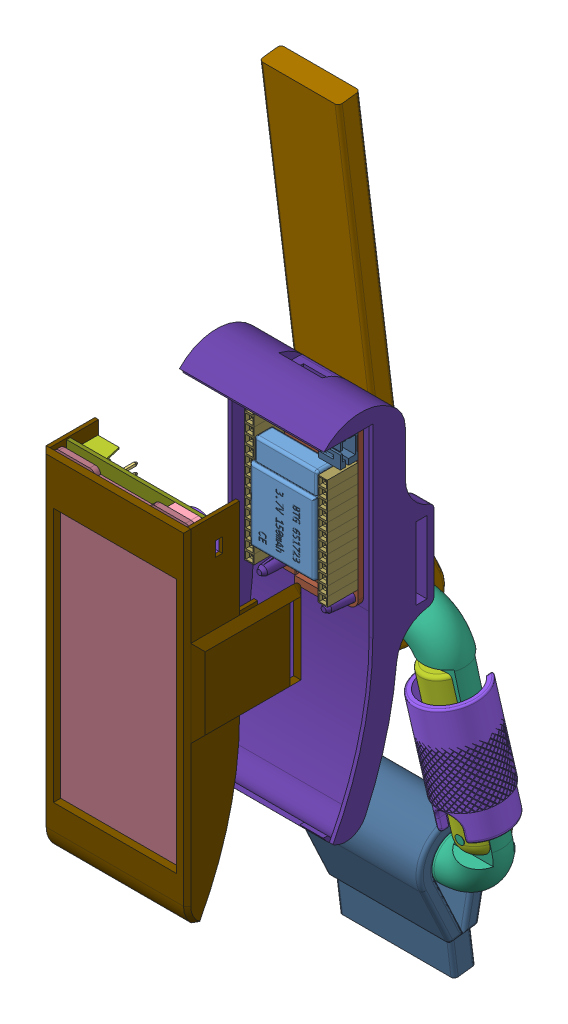
SolidWorks assembly PROTOTYPE4, configuration Default. Lengths in mm.
Overall size (66.23 222.78 90.92).
74 component instances, 29 part files, 212 mates.
Components (placement in the parent):
- P4_BTG 3.7V 150mAh LIPO-1: P4_BTG 3.7V 150mAh LIPO [Default] at (27.905 51.2971 -9.81) x (0 -1 0) z (-1 0 0) size (26 7 18.75)
- P4_CAPC-0805-T1.35-BN-1: P4_CAPC-0805-T1.35-BN [Default] at (18.3512 20.3637 36.1744) x (0 1 0) z (-1 0 0) size (2.1 1.35 1.35)
- P4_RESC-0805-1: P4_RESC-0805 [Default] at (24.182 63.4727 36.8494) x (-1 0 0) z (0 0 -1) size (2.1 1.35 0.6)
- P4_RESC-0805-2: P4_RESC-0805 [Default] at (24.1365 57.0909 36.8494) x (-1 0 0) z (0 0 -1) size (2.1 1.35 0.6)
- P4_RESC-0805-4: P4_RESC-0805 [Default] at (24.0502 60.9416 36.8494) x (1 0 0) z (0 0 -1) size (2.1 1.35 0.6)
- P4_soic-14-1: P4_soic-14 [Default] at (16.3896 59.7284 35.8715) x (0 -1 0) z (1 0 0) size (8.65 1.6 6.05)
- P4_MICRO_SD_WITH_SLOT-1: P4_MICRO_SD_WITH_SLOT [Default] at (56.0581 -187.6439 -84.5543) x (0 0 -1) z (0 1 0) size (2.44 17.9 16)
- P4_MS5611NOBREAKOUT-1: P4_MS5611NOBREAKOUT [Default] at (31.3803 12.3031 35.3494) x (0 1 0) z (-1 0 0) size (5.08 1.5 3.07)
- P4_TACTILE_SWITCH_SIDE-2: P4_TACTILE_SWITCH_SIDE [Default] at (3.8 59.5977 32.5638) x (0 1 0) z (0 0 1) size (6.8 8.34 8.73)
- P4_BOT-03D PASSIVE BUZZER-1: P4_BOT-03D PASSIVE BUZZER [Default] at (31.8 58.2086 36.5494) x (0 1 0) z (-1 0 0) size (12.6 3.6 11)
- P4_AB2_USB_MICRO_SMD-2: P4_AB2_USB_MICRO_SMD [Default] at (19.0065 148.0155 -12.6975) x (-1 0 0) z (0 1 0) size (7.99 3.56 5.59)
- P4_JST 2pin rightangle-2: P4_JST 2pin rightangle [Default] at (30.445 58.185 -12.31) x (0 1 0) z (1 0 0) size (8 6.3 7.62)
- P4_BLUEFRUIT FEATHER-2: P4_BLUEFRUIT FEATHER [Default] at (30.445 66 -13.81) x (0 -1 0) z (-1 0 0) size (50.98 4.5 22.86)
- P4_1PIN_8.25_SHORT_SOCKET-44: P4_1PIN_8.25_SHORT_SOCKET [Default] at (8.855 24 -12.31) x (0 1 0) z (0 0 1) size (2.54 2.54 11.81)
- P4_1PIN_8.25_SHORT_SOCKET-45: P4_1PIN_8.25_SHORT_SOCKET [Default] at (8.855 26.54 -12.31) x (0 1 0) z (0 0 1) size (2.54 2.54 11.81)
- P4_1PIN_8.25_SHORT_SOCKET-46: P4_1PIN_8.25_SHORT_SOCKET [Default] at (8.855 29.08 -12.31) x (0 1 0) z (0 0 1) size (2.54 2.54 11.81)
- P4_1PIN_8.25_SHORT_SOCKET-47: P4_1PIN_8.25_SHORT_SOCKET [Default] at (8.855 31.62 -12.31) x (0 1 0) z (0 0 1) size (2.54 2.54 11.81)
- P4_1PIN_8.25_SHORT_SOCKET-48: P4_1PIN_8.25_SHORT_SOCKET [Default] at (8.855 34.16 -12.31) x (0 1 0) z (0 0 1) size (2.54 2.54 11.81)
- P4_1PIN_8.25_SHORT_SOCKET-49: P4_1PIN_8.25_SHORT_SOCKET [Default] at (8.855 36.7 -12.31) x (0 1 0) z (0 0 1) size (2.54 2.54 11.81)
- P4_1PIN_8.25_SHORT_SOCKET-50: P4_1PIN_8.25_SHORT_SOCKET [Default] at (8.855 39.24 -12.31) x (0 1 0) z (0 0 1) size (2.54 2.54 11.81)
- P4_1PIN_8.25_SHORT_SOCKET-51: P4_1PIN_8.25_SHORT_SOCKET [Default] at (8.855 41.78 -12.31) x (0 1 0) z (0 0 1) size (2.54 2.54 11.81)
- P4_1PIN_8.25_SHORT_SOCKET-52: P4_1PIN_8.25_SHORT_SOCKET [Default] at (8.855 44.32 -12.31) x (0 1 0) z (0 0 1) size (2.54 2.54 11.81)
- P4_1PIN_8.25_SHORT_SOCKET-53: P4_1PIN_8.25_SHORT_SOCKET [Default] at (8.855 46.86 -12.31) x (0 1 0) z (0 0 1) size (2.54 2.54 11.81)
- P4_1PIN_8.25_SHORT_SOCKET-54: P4_1PIN_8.25_SHORT_SOCKET [Default] at (8.855 49.4 -12.31) x (0 1 0) z (0 0 1) size (2.54 2.54 11.81)
- P4_1PIN_8.25_SHORT_SOCKET-55: P4_1PIN_8.25_SHORT_SOCKET [Default] at (8.855 51.94 -12.31) x (0 1 0) z (0 0 1) size (2.54 2.54 11.81)
- P4_1PIN_8.25_SHORT_SOCKET-56: P4_1PIN_8.25_SHORT_SOCKET [Default] at (8.855 54.48 -12.31) x (0 1 0) z (0 0 1) size (2.54 2.54 11.81)
- P4_1PIN_8.25_SHORT_SOCKET-57: P4_1PIN_8.25_SHORT_SOCKET [Default] at (8.855 57.02 -12.31) x (0 1 0) z (0 0 1) size (2.54 2.54 11.81)
- P4_1PIN_8.25_SHORT_SOCKET-58: P4_1PIN_8.25_SHORT_SOCKET [Default] at (8.855 59.56 -12.31) x (0 1 0) z (0 0 1) size (2.54 2.54 11.81)
- P4_1PIN_8.25_SHORT_SOCKET-59: P4_1PIN_8.25_SHORT_SOCKET [Default] at (8.855 21.46 -12.31) x (0 1 0) z (0 0 1) size (2.54 2.54 11.81)
- P4_1PIN_8.25_SHORT_SOCKET-60: P4_1PIN_8.25_SHORT_SOCKET [Default] at (29.175 49.4 -12.31) x (0 1 0) z (0 0 1) size (2.54 2.54 11.81)
- P4_1PIN_8.25_SHORT_SOCKET-61: P4_1PIN_8.25_SHORT_SOCKET [Default] at (29.175 46.86 -12.31) x (0 1 0) z (0 0 1) size (2.54 2.54 11.81)
- P4_1PIN_8.25_SHORT_SOCKET-62: P4_1PIN_8.25_SHORT_SOCKET [Default] at (29.175 44.32 -12.31) x (0 1 0) z (0 0 1) size (2.54 2.54 11.81)
- P4_1PIN_8.25_SHORT_SOCKET-63: P4_1PIN_8.25_SHORT_SOCKET [Default] at (29.175 41.78 -12.31) x (0 1 0) z (0 0 1) size (2.54 2.54 11.81)
- P4_1PIN_8.25_SHORT_SOCKET-64: P4_1PIN_8.25_SHORT_SOCKET [Default] at (29.175 39.24 -12.31) x (0 1 0) z (0 0 1) size (2.54 2.54 11.81)
- P4_1PIN_8.25_SHORT_SOCKET-65: P4_1PIN_8.25_SHORT_SOCKET [Default] at (29.175 36.7 -12.31) x (0 1 0) z (0 0 1) size (2.54 2.54 11.81)
- P4_1PIN_8.25_SHORT_SOCKET-66: P4_1PIN_8.25_SHORT_SOCKET [Default] at (29.175 34.16 -12.31) x (0 1 0) z (0 0 1) size (2.54 2.54 11.81)
- P4_1PIN_8.25_SHORT_SOCKET-67: P4_1PIN_8.25_SHORT_SOCKET [Default] at (29.175 31.62 -12.31) x (0 1 0) z (0 0 1) size (2.54 2.54 11.81)
- P4_1PIN_8.25_SHORT_SOCKET-68: P4_1PIN_8.25_SHORT_SOCKET [Default] at (29.175 29.08 -12.31) x (0 1 0) z (0 0 1) size (2.54 2.54 11.81)
- P4_1PIN_8.25_SHORT_SOCKET-69: P4_1PIN_8.25_SHORT_SOCKET [Default] at (29.175 26.54 -12.31) x (0 1 0) z (0 0 1) size (2.54 2.54 11.81)
- P4_1PIN_8.25_SHORT_SOCKET-70: P4_1PIN_8.25_SHORT_SOCKET [Default] at (29.175 24 -12.31) x (0 1 0) z (0 0 1) size (2.54 2.54 11.81)
- P4_1PIN_8.25_SHORT_SOCKET-71: P4_1PIN_8.25_SHORT_SOCKET [Default] at (29.175 21.46 -12.31) x (0 1 0) z (0 0 1) size (2.54 2.54 11.81)
- Part2^PROTOTYPE4-1: Part2^PROTOTYPE4 [Default] at origin (virtual)
- P4_2.9_EPD-1: P4_2.9_EPD [Default] at (38 66.02 39.9794) x (-1 0 0) z (0 1 0) size (38 8.3 89.5)
  - P4_2.9_EPD-1: P4_2.9_EPD [Default] at origin size (38 3.55 89.5)
  - P4_JST XH 8 S8B-XH-A1 shrouded header connector v4-1: P4_JST XH 8 S8B-XH-A1 shrouded header connector v4 [Default] at (19 -2.875 -82.5) x (-1 0 0) z (0 0 -1) size (22.68 5.75 10.45)
  - P4_FPC_24-1: P4_FPC_24 [Valor predeterminado] at (23 -2.13 -7.2471) x (1 0 0) z (0 1 0) size (16.4 6.45 2.13)
- P4_PCB_FOR_2.9_EPD-1: P4_PCB_FOR_2.9_EPD [Default] at (0 66 37.8494) x (1 0 0) z (0 1 0) size (38 1 66)
- P4_2.9_EPD_CASE_BACK-1: P4_2.9_EPD_CASE_BACK [Default] at (38.015 -27.6516 -35.2894) x (0 1 0) z (-1 0 0) size (100.85 30.49 40)
- P4_2.9_EPD_CASE_COVER-1: P4_2.9_EPD_CASE_COVER [Default] at (0 -6.6251 42.5294) x (0 1 0) z (0 0 1) size (95.4 44 31.49)
- P4_SO8-1: P4_SO8 [Default] at (15.2666 50.6882 36.8494) x (1 0 0) z (0 1 0) size (5 1.75 6.2)
- P4_SOT23-1: P4_SOT23 [Predeterminado] at (22.8563 53.2581 36.1768) x (-1 0 0) z (0 0 -1) size (3 2.25 1.22)
- P4_RESC-0805-8: P4_RESC-0805 [Default] at (22.7629 48.0366 36.8494) x (0 1 0) z (0 0 -1) size (2.1 1.35 0.6)
- P4_878980426-1: P4_878980426 [Default] at (8.84 35.43 34.2844) x (0 1 0) z (-1 0 0) size (10.16 9.65 4.8)
- P4_878980426-2: P4_878980426 [Default] at (8.84 25.27 34.2844) x (0 1 0) z (-1 0 0) size (10.16 9.65 4.8)
- P4_878980426-3: P4_878980426 [Default] at (29.16 35.43 34.2844) x (0 1 0) z (-1 0 0) size (10.16 9.65 4.8)
- P4_878980426-4: P4_878980426 [Default] at (8.84 55.75 34.2844) x (0 1 0) z (-1 0 0) size (10.16 9.65 4.8)
- P4_878980426-5: P4_878980426 [Default] at (29.16 45.59 34.2844) x (0 1 0) z (-1 0 0) size (10.16 9.65 4.8)
- P4_878980426-6: P4_878980426 [Default] at (29.16 25.27 34.2844) x (0 1 0) z (-1 0 0) size (10.16 9.65 4.8)
- P4_878980426-7: P4_878980426 [Default] at (8.84 45.59 34.2844) x (0 1 0) z (-1 0 0) size (10.16 9.65 4.8)
- P4_SPACER-1: P4_SPACER [Default] at (38 -23.48 39.9794) x (-1 0 0) z (0 -1 0) size (38 3.13 70.25)
- P4_SMT_RA_PIN-1: P4_SMT_RA_PIN [Default] at (24.03 10.67 36.8494) x (0 -1 0) z (1 0 0) size (12.95 3.56 2.54)
- P4_SMT_RA_PIN-2: P4_SMT_RA_PIN [Default] at (26.57 10.67 36.8494) x (0 -1 0) z (1 0 0) size (12.95 3.56 2.54)
- P4_SMT_RA_PIN-3: P4_SMT_RA_PIN [Default] at (18.95 10.67 36.8494) x (0 -1 0) z (1 0 0) size (12.95 3.56 2.54)
- P4_SMT_RA_PIN-4: P4_SMT_RA_PIN [Default] at (21.49 10.67 36.8494) x (0 -1 0) z (1 0 0) size (12.95 3.56 2.54)
- P4_SMT_RA_PIN-5: P4_SMT_RA_PIN [Default] at (31.65 10.67 36.8494) x (0 -1 0) z (1 0 0) size (12.95 3.56 2.54)
- P4_SMT_RA_PIN-6: P4_SMT_RA_PIN [Default] at (29.11 10.67 36.8494) x (0 -1 0) z (1 0 0) size (12.95 3.56 2.54)
- P4_SMT_RA_PIN-7: P4_SMT_RA_PIN [Default] at (36.73 10.67 36.8494) x (0 -1 0) z (1 0 0) size (12.95 3.56 2.54)
- P4_SMT_RA_PIN-8: P4_SMT_RA_PIN [Default] at (34.19 10.67 36.8494) x (0 -1 0) z (1 0 0) size (12.95 3.56 2.54)
- CARABINER SUP AIR-1: CARABINER SUP AIR [Default] at (19.0561 -21.0823 -30.0124) x (1 0 0) z (0 -0.122208 0.992504) size (66.23 74 18.01)
  - CARABINER_MAIN-1: CARABINER_MAIN [Default] at origin size (63.85 74 12.79)
  - CARABINER_ARM-1: CARABINER_ARM [Default] at (26.2233 -22.952 0) x (0.990404 0.138202 0) z (0 0 1) size (12 45.37 12.12)
  - CARABINER_LOCK-1: CARABINER_LOCK [Default] at (25.3718 -16.8504 0) x (0.990404 0.138202 0) z (0 0 1) size (18.01 33.07 18.01)
- RISER-1: RISER [Default] at (7.015 9.6853 -26.2239) x (1 0 0) z (0 -0.122208 0.992504) size (24 140 20)
- HARNESS-1: HARNESS [Default] at (1.9827 -51.85 -33.8009) x (1 0 0) z (0 0.122208 -0.992504) size (34 40 20)
Mates (geometry in assembly coordinates):
- Coincident628: coincident anti-aligned: plane of P4_BTG 3.7V 150mAh LIPO-1 through (27.905 51.2971 -9.81) normal (0 0 -1); plane of P4_BLUEFRUIT FEATHER-2 through (30.445 66 -9.81) normal (0 0 1)
- Coincident376: coincident aligned: plane of P4_PCB_FOR_2.9_EPD-1 through (0 66 36.8494) normal (-1 0 0); plane of P4_TACTILE_SWITCH_SIDE-2 through (0 59.5977 32.5638) normal (-1 0 0)
- Coincident433: coincident anti-aligned: plane of P4_AB2_USB_MICRO_SMD-2 through (19.0065 66 -12.31) normal (0 0 -1); plane of P4_BLUEFRUIT FEATHER-2 through (27.815 17.65 -12.31) normal (0 0 1)
- Parallel22: parallel aligned: line of P4_AB2_USB_MICRO_SMD-2 through (21.4522 66 -12.3752) axis (-1 0 0); line of P4_BLUEFRUIT FEATHER-2 through (27.815 66 -12.31) axis (-1 0 0)
- Coincident434: coincident aligned: plane of P4_JST 2pin rightangle-2 through (30.445 52.4192 -12.31) normal (1 0 0); plane of P4_BLUEFRUIT FEATHER-2 through (30.445 63.37 -12.31) normal (1 0 0)
- Coincident435: coincident: line of P4_AB2_USB_MICRO_SMD-2 through (21.9513 66 -9.7692) axis (-1 0 0); plane of P4_BLUEFRUIT FEATHER-2 through (27.815 66 -12.31) normal (0 1 0)
- Coincident436: coincident anti-aligned: plane of P4_JST 2pin rightangle-2 through (26.635 55.3021 -12.31) normal (0 0 -1); plane of P4_BLUEFRUIT FEATHER-2 through (27.815 17.65 -12.31) normal (0 0 1)
- Distance27: distance = 6.7 mm aligned: plane of P4_JST 2pin rightangle-2 through (30.445 59.3 -12.31) normal (0 1 0); plane of P4_BLUEFRUIT FEATHER-2 through (27.815 66 -12.31) normal (0 1 0)
- Parallel23: parallel aligned: plane of P4_BOT-03D PASSIVE BUZZER-1 through (38 55.7086 33.2494) normal (1 0 0); plane of P4_BLUEFRUIT FEATHER-2 through (30.445 63.37 -12.31) normal (1 0 0)
- LimitDistance11: limit distance = 0.0071 mm anti-aligned: plane of P4_BTG 3.7V 150mAh LIPO-1 through (27.905 51.2971 -2.81) normal (0 1 0); plane of P4_JST 2pin rightangle-2 through (30.445 51.3042 -12.31) normal (0 -1 0)
- Coincident458: coincident aligned: plane of P4_1PIN_8.25_SHORT_SOCKET-57 through (7.585 57.02 -3.81) normal (-1 0 0); plane of P4_1PIN_8.25_SHORT_SOCKET-58 through (7.585 59.56 -3.81) normal (-1 0 0)
- Coincident459: coincident aligned: plane of P4_1PIN_8.25_SHORT_SOCKET-56 through (7.585 54.48 -3.81) normal (-1 0 0); plane of P4_1PIN_8.25_SHORT_SOCKET-57 through (7.585 57.02 -3.81) normal (-1 0 0)
- Coincident460: coincident aligned: plane of P4_1PIN_8.25_SHORT_SOCKET-55 through (7.585 51.94 -3.81) normal (-1 0 0); plane of P4_1PIN_8.25_SHORT_SOCKET-56 through (7.585 54.48 -3.81) normal (-1 0 0)
- Coincident461: coincident aligned: plane of P4_1PIN_8.25_SHORT_SOCKET-54 through (7.585 49.4 -3.81) normal (-1 0 0); plane of P4_1PIN_8.25_SHORT_SOCKET-55 through (7.585 51.94 -3.81) normal (-1 0 0)
- Coincident462: coincident aligned: plane of P4_1PIN_8.25_SHORT_SOCKET-53 through (7.585 46.86 -3.81) normal (-1 0 0); plane of P4_1PIN_8.25_SHORT_SOCKET-54 through (7.585 49.4 -3.81) normal (-1 0 0)
- Coincident463: coincident aligned: plane of P4_1PIN_8.25_SHORT_SOCKET-52 through (7.585 44.32 -3.81) normal (-1 0 0); plane of P4_1PIN_8.25_SHORT_SOCKET-53 through (7.585 46.86 -3.81) normal (-1 0 0)
- Coincident464: coincident aligned: plane of P4_1PIN_8.25_SHORT_SOCKET-51 through (7.585 41.78 -3.81) normal (-1 0 0); plane of P4_1PIN_8.25_SHORT_SOCKET-52 through (7.585 44.32 -3.81) normal (-1 0 0)
- Coincident465: coincident aligned: plane of P4_1PIN_8.25_SHORT_SOCKET-50 through (7.585 39.24 -3.81) normal (-1 0 0); plane of P4_1PIN_8.25_SHORT_SOCKET-51 through (7.585 41.78 -3.81) normal (-1 0 0)
- Coincident466: coincident aligned: plane of P4_1PIN_8.25_SHORT_SOCKET-49 through (7.585 36.7 -3.81) normal (-1 0 0); plane of P4_1PIN_8.25_SHORT_SOCKET-50 through (7.585 39.24 -3.81) normal (-1 0 0)
- Coincident467: coincident aligned: plane of P4_1PIN_8.25_SHORT_SOCKET-48 through (7.585 34.16 -3.81) normal (-1 0 0); plane of P4_1PIN_8.25_SHORT_SOCKET-49 through (7.585 36.7 -3.81) normal (-1 0 0)
- Coincident468: coincident aligned: plane of P4_1PIN_8.25_SHORT_SOCKET-47 through (7.585 31.62 -3.81) normal (-1 0 0); plane of P4_1PIN_8.25_SHORT_SOCKET-48 through (7.585 34.16 -3.81) normal (-1 0 0)
- Coincident469: coincident aligned: plane of P4_1PIN_8.25_SHORT_SOCKET-46 through (7.585 29.08 -3.81) normal (-1 0 0); plane of P4_1PIN_8.25_SHORT_SOCKET-47 through (7.585 31.62 -3.81) normal (-1 0 0)
- Coincident470: coincident aligned: plane of P4_1PIN_8.25_SHORT_SOCKET-45 through (7.585 26.54 -3.81) normal (-1 0 0); plane of P4_1PIN_8.25_SHORT_SOCKET-46 through (7.585 29.08 -3.81) normal (-1 0 0)
- Coincident471: coincident aligned: plane of P4_1PIN_8.25_SHORT_SOCKET-44 through (7.585 24 -3.81) normal (-1 0 0); plane of P4_1PIN_8.25_SHORT_SOCKET-45 through (7.585 26.54 -3.81) normal (-1 0 0)
- Coincident472: coincident anti-aligned: plane of P4_1PIN_8.25_SHORT_SOCKET-57 through (8.855 58.29 -3.81) normal (0 1 0); plane of P4_1PIN_8.25_SHORT_SOCKET-58 through (8.855 58.29 -3.81) normal (0 -1 0)
- Coincident473: coincident anti-aligned: plane of P4_1PIN_8.25_SHORT_SOCKET-56 through (8.855 55.75 -3.81) normal (0 1 0); plane of P4_1PIN_8.25_SHORT_SOCKET-57 through (8.855 55.75 -3.81) normal (0 -1 0)
- Coincident474: coincident anti-aligned: plane of P4_1PIN_8.25_SHORT_SOCKET-55 through (8.855 53.21 -3.81) normal (0 1 0); plane of P4_1PIN_8.25_SHORT_SOCKET-56 through (8.855 53.21 -3.81) normal (0 -1 0)
- Coincident475: coincident anti-aligned: plane of P4_1PIN_8.25_SHORT_SOCKET-54 through (8.855 50.67 -3.81) normal (0 1 0); plane of P4_1PIN_8.25_SHORT_SOCKET-55 through (8.855 50.67 -3.81) normal (0 -1 0)
- Coincident476: coincident anti-aligned: plane of P4_1PIN_8.25_SHORT_SOCKET-53 through (8.855 48.13 -3.81) normal (0 1 0); plane of P4_1PIN_8.25_SHORT_SOCKET-54 through (8.855 48.13 -3.81) normal (0 -1 0)
- Coincident477: coincident anti-aligned: plane of P4_1PIN_8.25_SHORT_SOCKET-52 through (8.855 45.59 -3.81) normal (0 1 0); plane of P4_1PIN_8.25_SHORT_SOCKET-53 through (8.855 45.59 -3.81) normal (0 -1 0)
- Coincident478: coincident anti-aligned: plane of P4_1PIN_8.25_SHORT_SOCKET-51 through (8.855 43.05 -3.81) normal (0 1 0); plane of P4_1PIN_8.25_SHORT_SOCKET-52 through (8.855 43.05 -3.81) normal (0 -1 0)
- Coincident479: coincident anti-aligned: plane of P4_1PIN_8.25_SHORT_SOCKET-50 through (8.855 40.51 -3.81) normal (0 1 0); plane of P4_1PIN_8.25_SHORT_SOCKET-51 through (8.855 40.51 -3.81) normal (0 -1 0)
- Coincident480: coincident anti-aligned: plane of P4_1PIN_8.25_SHORT_SOCKET-49 through (8.855 37.97 -3.81) normal (0 1 0); plane of P4_1PIN_8.25_SHORT_SOCKET-50 through (8.855 37.97 -3.81) normal (0 -1 0)
- Coincident481: coincident anti-aligned: plane of P4_1PIN_8.25_SHORT_SOCKET-48 through (8.855 35.43 -3.81) normal (0 1 0); plane of P4_1PIN_8.25_SHORT_SOCKET-49 through (8.855 35.43 -3.81) normal (0 -1 0)
- Coincident482: coincident anti-aligned: plane of P4_1PIN_8.25_SHORT_SOCKET-47 through (8.855 32.89 -3.81) normal (0 1 0); plane of P4_1PIN_8.25_SHORT_SOCKET-48 through (8.855 32.89 -3.81) normal (0 -1 0)
- Coincident483: coincident anti-aligned: plane of P4_1PIN_8.25_SHORT_SOCKET-46 through (8.855 30.35 -3.81) normal (0 1 0); plane of P4_1PIN_8.25_SHORT_SOCKET-47 through (8.855 30.35 -3.81) normal (0 -1 0)
- Coincident484: coincident anti-aligned: plane of P4_1PIN_8.25_SHORT_SOCKET-45 through (8.855 27.81 -3.81) normal (0 1 0); plane of P4_1PIN_8.25_SHORT_SOCKET-46 through (8.855 27.81 -3.81) normal (0 -1 0)
- Coincident485: coincident anti-aligned: plane of P4_1PIN_8.25_SHORT_SOCKET-44 through (8.855 25.27 -3.81) normal (0 1 0); plane of P4_1PIN_8.25_SHORT_SOCKET-45 through (8.855 25.27 -3.81) normal (0 -1 0)
- Coincident486: coincident aligned: plane of P4_1PIN_8.25_SHORT_SOCKET-57 through (8.855 57.02 -3.81) normal (0 0 1); plane of P4_1PIN_8.25_SHORT_SOCKET-58 through (8.855 59.56 -3.81) normal (0 0 1)
- Coincident487: coincident aligned: plane of P4_1PIN_8.25_SHORT_SOCKET-56 through (8.855 54.48 -3.81) normal (0 0 1); plane of P4_1PIN_8.25_SHORT_SOCKET-57 through (8.855 57.02 -3.81) normal (0 0 1)
- Coincident488: coincident aligned: plane of P4_1PIN_8.25_SHORT_SOCKET-55 through (8.855 51.94 -3.81) normal (0 0 1); plane of P4_1PIN_8.25_SHORT_SOCKET-56 through (8.855 54.48 -3.81) normal (0 0 1)
- Coincident489: coincident aligned: plane of P4_1PIN_8.25_SHORT_SOCKET-54 through (8.855 49.4 -3.81) normal (0 0 1); plane of P4_1PIN_8.25_SHORT_SOCKET-55 through (8.855 51.94 -3.81) normal (0 0 1)
- Coincident490: coincident aligned: plane of P4_1PIN_8.25_SHORT_SOCKET-53 through (8.855 46.86 -3.81) normal (0 0 1); plane of P4_1PIN_8.25_SHORT_SOCKET-54 through (8.855 49.4 -3.81) normal (0 0 1)
- Coincident491: coincident aligned: plane of P4_1PIN_8.25_SHORT_SOCKET-52 through (8.855 44.32 -3.81) normal (0 0 1); plane of P4_1PIN_8.25_SHORT_SOCKET-53 through (8.855 46.86 -3.81) normal (0 0 1)
- Coincident492: coincident aligned: plane of P4_1PIN_8.25_SHORT_SOCKET-51 through (8.855 41.78 -3.81) normal (0 0 1); plane of P4_1PIN_8.25_SHORT_SOCKET-52 through (8.855 44.32 -3.81) normal (0 0 1)
- Coincident493: coincident aligned: plane of P4_1PIN_8.25_SHORT_SOCKET-50 through (8.855 39.24 -3.81) normal (0 0 1); plane of P4_1PIN_8.25_SHORT_SOCKET-51 through (8.855 41.78 -3.81) normal (0 0 1)
- Coincident494: coincident aligned: plane of P4_1PIN_8.25_SHORT_SOCKET-49 through (8.855 36.7 -3.81) normal (0 0 1); plane of P4_1PIN_8.25_SHORT_SOCKET-50 through (8.855 39.24 -3.81) normal (0 0 1)
- Coincident495: coincident aligned: plane of P4_1PIN_8.25_SHORT_SOCKET-48 through (8.855 34.16 -3.81) normal (0 0 1); plane of P4_1PIN_8.25_SHORT_SOCKET-49 through (8.855 36.7 -3.81) normal (0 0 1)
- Coincident496: coincident aligned: plane of P4_1PIN_8.25_SHORT_SOCKET-47 through (8.855 31.62 -3.81) normal (0 0 1); plane of P4_1PIN_8.25_SHORT_SOCKET-48 through (8.855 34.16 -3.81) normal (0 0 1)
- Coincident497: coincident aligned: plane of P4_1PIN_8.25_SHORT_SOCKET-46 through (8.855 29.08 -3.81) normal (0 0 1); plane of P4_1PIN_8.25_SHORT_SOCKET-47 through (8.855 31.62 -3.81) normal (0 0 1)
- Coincident498: coincident aligned: plane of P4_1PIN_8.25_SHORT_SOCKET-45 through (8.855 26.54 -3.81) normal (0 0 1); plane of P4_1PIN_8.25_SHORT_SOCKET-46 through (8.855 29.08 -3.81) normal (0 0 1)
- Coincident499: coincident aligned: plane of P4_1PIN_8.25_SHORT_SOCKET-44 through (8.855 24 -3.81) normal (0 0 1); plane of P4_1PIN_8.25_SHORT_SOCKET-45 through (8.855 26.54 -3.81) normal (0 0 1)
- Coincident500: coincident anti-aligned: plane of P4_BLUEFRUIT FEATHER-2 through (27.815 17.65 -12.31) normal (0 0 1); plane of P4_1PIN_8.25_SHORT_SOCKET-44 through (8.855 24 -12.31) normal (0 0 -1)
- Coincident501: coincident aligned: plane of P4_1PIN_8.25_SHORT_SOCKET-58 through (7.585 59.56 -3.81) normal (-1 0 0); plane of P4_BLUEFRUIT FEATHER-2 through (7.585 63.37 -12.31) normal (-1 0 0)
- Coincident502: coincident aligned: plane of P4_1PIN_8.25_SHORT_SOCKET-44 through (7.585 24 -3.81) normal (-1 0 0); plane of P4_1PIN_8.25_SHORT_SOCKET-59 through (7.585 21.46 -3.81) normal (-1 0 0)
- Coincident503: coincident anti-aligned: plane of P4_1PIN_8.25_SHORT_SOCKET-44 through (8.855 22.73 -3.81) normal (0 -1 0); plane of P4_1PIN_8.25_SHORT_SOCKET-59 through (8.855 22.73 -3.81) normal (0 1 0)
- Coincident504: coincident aligned: plane of P4_1PIN_8.25_SHORT_SOCKET-44 through (8.855 24 -3.81) normal (0 0 1); plane of P4_1PIN_8.25_SHORT_SOCKET-59 through (8.855 21.46 -3.81) normal (0 0 1)
- Width9: width anti-aligned: plane of P4_1PIN_8.25_SHORT_SOCKET-58 through (8.855 60.83 -3.81) normal (0 1 0); plane of P4_1PIN_8.25_SHORT_SOCKET-59 through (8.855 20.19 -3.81) normal (0 -1 0); plane of P4_BLUEFRUIT FEATHER-2 through (27.815 15.02 -12.31) normal (0 -1 0); plane of P4_BLUEFRUIT FEATHER-2 through (27.815 66 -12.31) normal (0 1 0)
- Coincident505: coincident anti-aligned: plane of P4_1PIN_8.25_SHORT_SOCKET-60 through (29.175 48.13 -3.81) normal (0 -1 0); plane of P4_1PIN_8.25_SHORT_SOCKET-61 through (29.175 48.13 -3.81) normal (0 1 0)
- Coincident506: coincident anti-aligned: plane of P4_1PIN_8.25_SHORT_SOCKET-70 through (29.175 22.73 -3.81) normal (0 -1 0); plane of P4_1PIN_8.25_SHORT_SOCKET-71 through (29.175 22.73 -3.81) normal (0 1 0)
- Coincident507: coincident aligned: plane of P4_1PIN_8.25_SHORT_SOCKET-63 through (27.905 41.78 -3.81) normal (-1 0 0); plane of P4_1PIN_8.25_SHORT_SOCKET-64 through (27.905 39.24 -3.81) normal (-1 0 0)
- Coincident508: coincident aligned: plane of P4_1PIN_8.25_SHORT_SOCKET-61 through (27.905 46.86 -3.81) normal (-1 0 0); plane of P4_1PIN_8.25_SHORT_SOCKET-62 through (27.905 44.32 -3.81) normal (-1 0 0)
- Coincident509: coincident aligned: plane of P4_1PIN_8.25_SHORT_SOCKET-62 through (27.905 44.32 -3.81) normal (-1 0 0); plane of P4_1PIN_8.25_SHORT_SOCKET-63 through (27.905 41.78 -3.81) normal (-1 0 0)
- Coincident510: coincident aligned: plane of P4_1PIN_8.25_SHORT_SOCKET-66 through (27.905 34.16 -3.81) normal (-1 0 0); plane of P4_1PIN_8.25_SHORT_SOCKET-67 through (27.905 31.62 -3.81) normal (-1 0 0)
- Coincident511: coincident aligned: plane of P4_1PIN_8.25_SHORT_SOCKET-65 through (27.905 36.7 -3.81) normal (-1 0 0); plane of P4_1PIN_8.25_SHORT_SOCKET-66 through (27.905 34.16 -3.81) normal (-1 0 0)
- Coincident512: coincident aligned: plane of P4_1PIN_8.25_SHORT_SOCKET-68 through (27.905 29.08 -3.81) normal (-1 0 0); plane of P4_1PIN_8.25_SHORT_SOCKET-69 through (27.905 26.54 -3.81) normal (-1 0 0)
- Coincident513: coincident aligned: plane of P4_1PIN_8.25_SHORT_SOCKET-67 through (27.905 31.62 -3.81) normal (-1 0 0); plane of P4_1PIN_8.25_SHORT_SOCKET-68 through (27.905 29.08 -3.81) normal (-1 0 0)
- Coincident514: coincident aligned: plane of P4_1PIN_8.25_SHORT_SOCKET-69 through (27.905 26.54 -3.81) normal (-1 0 0); plane of P4_1PIN_8.25_SHORT_SOCKET-70 through (27.905 24 -3.81) normal (-1 0 0)
- Coincident515: coincident aligned: plane of P4_1PIN_8.25_SHORT_SOCKET-70 through (27.905 24 -3.81) normal (-1 0 0); plane of P4_1PIN_8.25_SHORT_SOCKET-71 through (27.905 21.46 -3.81) normal (-1 0 0)
- Coincident516: coincident aligned: plane of P4_1PIN_8.25_SHORT_SOCKET-60 through (27.905 49.4 -3.81) normal (-1 0 0); plane of P4_1PIN_8.25_SHORT_SOCKET-61 through (27.905 46.86 -3.81) normal (-1 0 0)
- Coincident517: coincident aligned: plane of P4_1PIN_8.25_SHORT_SOCKET-64 through (27.905 39.24 -3.81) normal (-1 0 0); plane of P4_1PIN_8.25_SHORT_SOCKET-65 through (27.905 36.7 -3.81) normal (-1 0 0)
- Coincident518: coincident anti-aligned: plane of P4_1PIN_8.25_SHORT_SOCKET-62 through (29.175 43.05 -3.81) normal (0 -1 0); plane of P4_1PIN_8.25_SHORT_SOCKET-63 through (29.175 43.05 -3.81) normal (0 1 0)
- Coincident519: coincident anti-aligned: plane of P4_1PIN_8.25_SHORT_SOCKET-63 through (29.175 40.51 -3.81) normal (0 -1 0); plane of P4_1PIN_8.25_SHORT_SOCKET-64 through (29.175 40.51 -3.81) normal (0 1 0)
- Coincident520: coincident anti-aligned: plane of P4_1PIN_8.25_SHORT_SOCKET-65 through (29.175 35.43 -3.81) normal (0 -1 0); plane of P4_1PIN_8.25_SHORT_SOCKET-66 through (29.175 35.43 -3.81) normal (0 1 0)
- Coincident521: coincident anti-aligned: plane of P4_1PIN_8.25_SHORT_SOCKET-66 through (29.175 32.89 -3.81) normal (0 -1 0); plane of P4_1PIN_8.25_SHORT_SOCKET-67 through (29.175 32.89 -3.81) normal (0 1 0)
- Coincident522: coincident anti-aligned: plane of P4_1PIN_8.25_SHORT_SOCKET-61 through (29.175 45.59 -3.81) normal (0 -1 0); plane of P4_1PIN_8.25_SHORT_SOCKET-62 through (29.175 45.59 -3.81) normal (0 1 0)
- Coincident523: coincident anti-aligned: plane of P4_1PIN_8.25_SHORT_SOCKET-67 through (29.175 30.35 -3.81) normal (0 -1 0); plane of P4_1PIN_8.25_SHORT_SOCKET-68 through (29.175 30.35 -3.81) normal (0 1 0)
- Coincident524: coincident anti-aligned: plane of P4_1PIN_8.25_SHORT_SOCKET-69 through (29.175 25.27 -3.81) normal (0 -1 0); plane of P4_1PIN_8.25_SHORT_SOCKET-70 through (29.175 25.27 -3.81) normal (0 1 0)
- Coincident525: coincident anti-aligned: plane of P4_1PIN_8.25_SHORT_SOCKET-64 through (29.175 37.97 -3.81) normal (0 -1 0); plane of P4_1PIN_8.25_SHORT_SOCKET-65 through (29.175 37.97 -3.81) normal (0 1 0)
- Coincident526: coincident anti-aligned: plane of P4_1PIN_8.25_SHORT_SOCKET-68 through (29.175 27.81 -3.81) normal (0 -1 0); plane of P4_1PIN_8.25_SHORT_SOCKET-69 through (29.175 27.81 -3.81) normal (0 1 0)
- Coincident527: coincident aligned: plane of P4_1PIN_8.25_SHORT_SOCKET-65 through (29.175 36.7 -3.81) normal (0 0 1); plane of P4_1PIN_8.25_SHORT_SOCKET-66 through (29.175 34.16 -3.81) normal (0 0 1)
- Coincident528: coincident aligned: plane of P4_1PIN_8.25_SHORT_SOCKET-68 through (29.175 29.08 -3.81) normal (0 0 1); plane of P4_1PIN_8.25_SHORT_SOCKET-69 through (29.175 26.54 -3.81) normal (0 0 1)
- Coincident529: coincident aligned: plane of P4_1PIN_8.25_SHORT_SOCKET-62 through (29.175 44.32 -3.81) normal (0 0 1); plane of P4_1PIN_8.25_SHORT_SOCKET-63 through (29.175 41.78 -3.81) normal (0 0 1)
- Coincident530: coincident aligned: plane of P4_1PIN_8.25_SHORT_SOCKET-64 through (29.175 39.24 -3.81) normal (0 0 1); plane of P4_1PIN_8.25_SHORT_SOCKET-65 through (29.175 36.7 -3.81) normal (0 0 1)
- Coincident531: coincident aligned: plane of P4_1PIN_8.25_SHORT_SOCKET-70 through (29.175 24 -3.81) normal (0 0 1); plane of P4_1PIN_8.25_SHORT_SOCKET-71 through (29.175 21.46 -3.81) normal (0 0 1)
- Coincident532: coincident aligned: plane of P4_1PIN_8.25_SHORT_SOCKET-63 through (29.175 41.78 -3.81) normal (0 0 1); plane of P4_1PIN_8.25_SHORT_SOCKET-64 through (29.175 39.24 -3.81) normal (0 0 1)
- Coincident533: coincident aligned: plane of P4_1PIN_8.25_SHORT_SOCKET-60 through (29.175 49.4 -3.81) normal (0 0 1); plane of P4_1PIN_8.25_SHORT_SOCKET-61 through (29.175 46.86 -3.81) normal (0 0 1)
- Coincident534: coincident aligned: plane of P4_1PIN_8.25_SHORT_SOCKET-61 through (29.175 46.86 -3.81) normal (0 0 1); plane of P4_1PIN_8.25_SHORT_SOCKET-62 through (29.175 44.32 -3.81) normal (0 0 1)
- Coincident535: coincident aligned: plane of P4_1PIN_8.25_SHORT_SOCKET-67 through (29.175 31.62 -3.81) normal (0 0 1); plane of P4_1PIN_8.25_SHORT_SOCKET-68 through (29.175 29.08 -3.81) normal (0 0 1)
- Coincident536: coincident aligned: plane of P4_1PIN_8.25_SHORT_SOCKET-66 through (29.175 34.16 -3.81) normal (0 0 1); plane of P4_1PIN_8.25_SHORT_SOCKET-67 through (29.175 31.62 -3.81) normal (0 0 1)
- Coincident537: coincident aligned: plane of P4_1PIN_8.25_SHORT_SOCKET-69 through (29.175 26.54 -3.81) normal (0 0 1); plane of P4_1PIN_8.25_SHORT_SOCKET-70 through (29.175 24 -3.81) normal (0 0 1)
- Coincident538: coincident aligned: plane of P4_BLUEFRUIT FEATHER-2 through (30.445 63.37 -12.31) normal (1 0 0); plane of P4_1PIN_8.25_SHORT_SOCKET-71 through (30.445 21.46 -3.81) normal (1 0 0)
- Coincident539: coincident aligned: plane of P4_1PIN_8.25_SHORT_SOCKET-59 through (8.855 20.19 -3.81) normal (0 -1 0); plane of P4_1PIN_8.25_SHORT_SOCKET-71 through (29.175 20.19 -3.81) normal (0 -1 0)
- Coincident540: coincident aligned: plane of P4_1PIN_8.25_SHORT_SOCKET-59 through (8.855 21.46 -3.81) normal (0 0 1); plane of P4_1PIN_8.25_SHORT_SOCKET-71 through (29.175 21.46 -3.81) normal (0 0 1)
- Coincident627: coincident anti-aligned: plane of P4_BTG 3.7V 150mAh LIPO-1 through (27.905 51.2971 -2.81) normal (1 0 0); plane of P4_1PIN_8.25_SHORT_SOCKET-60 through (27.905 49.4 -3.81) normal (-1 0 0)
- Parallel29: parallel aligned: plane of P4_BLUEFRUIT FEATHER-2 through (30.445 63.37 -12.31) normal (1 0 0); plane of P4_2.9_EPD-1/P4_2.9_EPD-1 through (38 64.52 41.4794) normal (1 0 0)
- Coincident640: coincident aligned: plane of P4_BLUEFRUIT FEATHER-2 through (27.815 66 -12.31) normal (0 1 0); plane of P4_PCB_FOR_2.9_EPD-1 through (0 66 36.8494) normal (0 1 0)
- Concentric36: concentric aligned: cylinder of P4_BLUEFRUIT FEATHER-2 through (10.125 17.65 -12.31) axis (0 0 -1) radius 1.5; cylinder of P4_2.9_EPD_CASE_BACK-1 through (10.125 17.65 -12.31) axis (0 0 -1) radius 1.5
- Concentric37: concentric aligned: cylinder of P4_BLUEFRUIT FEATHER-2 through (18.17 7.7595 -20.355) axis (0 1 0) radius 1.5; cylinder of P4_2.9_EPD_CASE_BACK-1 through (18.17 7.2595 -20.355) axis (0 1 0) radius 1.5
- Coincident642: coincident anti-aligned: plane of P4_BLUEFRUIT FEATHER-2 through (27.815 17.65 -13.81) normal (0 0 -1); plane of P4_2.9_EPD_CASE_BACK-1 through (0.015 -27.6516 -13.81) normal (0 0 1)
- Concentric38: concentric anti-aligned: cylinder of P4_2.9_EPD-1/P4_2.9_EPD-1 through (2.5 63.52 41.4794) axis (0 0 -1) radius 1.25; cylinder of P4_2.9_EPD_CASE_COVER-1 through (2.5 63.52 39.5294) axis (0 0 1) radius 1.25
- Concentric39: concentric anti-aligned: cylinder of P4_2.9_EPD-1/P4_2.9_EPD-1 through (35.5 63.52 41.4794) axis (0 0 -1) radius 1.25; cylinder of P4_2.9_EPD_CASE_COVER-1 through (35.5 63.52 39.5294) axis (0 0 1) radius 1.25
- Coincident645: coincident anti-aligned: plane of P4_2.9_EPD-1/P4_2.9_EPD-1 through (38 66.02 42.5294) normal (0 0 1); plane of P4_2.9_EPD_CASE_COVER-1 through (0 -6.6251 42.5294) normal (0 0 -1)
- Distance28: distance = 8.2058 mm: line of P4_AB2_USB_MICRO_SMD-2 through (15.7873 63.7041 -12.0707) axis (0 -1 0); line of P4_BLUEFRUIT FEATHER-2 through (7.585 63.37 -12.31) axis (0 -1 0)
- Width11: width anti-aligned: plane of P4_2.9_EPD-1/P4_2.9_EPD-1 through (0 64.52 41.4794) normal (-1 0 0); plane of P4_2.9_EPD-1/P4_2.9_EPD-1 through (38 64.52 41.4794) normal (1 0 0); plane of P4_PCB_FOR_2.9_EPD-1 through (38 66 36.8494) normal (1 0 0); plane of P4_PCB_FOR_2.9_EPD-1 through (0 66 36.8494) normal (-1 0 0)
- Coincident648: coincident anti-aligned: plane of P4_2.9_EPD-1/P4_2.9_EPD-1 through (10 66.02 41.4794) normal (0 1 0); plane of P4_2.9_EPD_CASE_BACK-1 through (0.015 66.02 -35.2894) normal (0 -1 0)
- Coincident650: coincident anti-aligned: plane of P4_CAPC-0805-T1.35-BN-1 through (18.3512 20.3637 36.8494) normal (0 0 1); plane of P4_PCB_FOR_2.9_EPD-1 through (0 66 36.8494) normal (0 0 -1)
- Coincident651: coincident anti-aligned: plane of P4_MS5611NOBREAKOUT-1 through (31.3803 12.3031 36.8494) normal (0 0 1); plane of P4_PCB_FOR_2.9_EPD-1 through (0 66 36.8494) normal (0 0 -1)
- Coincident652: coincident anti-aligned: plane of P4_TACTILE_SWITCH_SIDE-2 through (4.917 56.1977 36.8494) normal (0 0 1); plane of P4_PCB_FOR_2.9_EPD-1 through (0 66 36.8494) normal (0 0 -1)
- Coincident653: coincident anti-aligned: plane of P4_MICRO_SD_WITH_SLOT-1 through (6.0767 17.9614 36.8494) normal (0 0 1); plane of P4_PCB_FOR_2.9_EPD-1 through (0 66 36.8494) normal (0 0 -1)
- Coincident654: coincident: line of P4_soic-14-1 through (13.3812 56.1026 36.8494) axis (0 -1 0); plane of P4_PCB_FOR_2.9_EPD-1 through (0 66 36.8494) normal (0 0 -1)
- Coincident655: coincident: line of P4_soic-14-1 through (19.398 55.7343 36.8494) axis (0 1 0); plane of P4_PCB_FOR_2.9_EPD-1 through (0 66 36.8494) normal (0 0 -1)
- Coincident656: coincident anti-aligned: plane of P4_RESC-0805-2 through (23.1365 56.4159 36.8494) normal (0 0 1); plane of P4_PCB_FOR_2.9_EPD-1 through (0 66 36.8494) normal (0 0 -1)
- Coincident657: coincident anti-aligned: plane of P4_RESC-0805-1 through (23.182 62.7977 36.8494) normal (0 0 1); plane of P4_PCB_FOR_2.9_EPD-1 through (0 66 36.8494) normal (0 0 -1)
- Coincident658: coincident anti-aligned: plane of P4_RESC-0805-4 through (23.4002 61.6166 36.8494) normal (0 0 1); plane of P4_PCB_FOR_2.9_EPD-1 through (0 66 36.8494) normal (0 0 -1)
- Coincident659: coincident anti-aligned: plane of P4_PCB_FOR_2.9_EPD-1 through (0 66 36.8494) normal (0 0 -1); plane of P4_RESC-0805-8 through (22.0879 49.0366 36.8494) normal (0 0 1)
- Coincident660: coincident anti-aligned: plane of P4_PCB_FOR_2.9_EPD-1 through (0 66 36.8494) normal (0 0 -1); plane of P4_SOT23-1 through (21.3443 52.317 36.8494) normal (0 0 1)
- Coincident661: coincident anti-aligned: plane of P4_PCB_FOR_2.9_EPD-1 through (0 66 36.8494) normal (0 0 -1); plane of P4_SO8-1 through (16.9716 53.1882 36.8494) normal (0 0 1)
- Parallel31: parallel aligned: line of P4_PCB_FOR_2.9_EPD-1 through (0 66 36.8494) axis (1 0 0); line of P4_SO8-1 through (15.7016 53.7882 36.8494) axis (1 0 0)
- Coincident663: coincident anti-aligned: plane of P4_878980426-3 through (29.16 40.51 34.2844) normal (0 1 0); plane of P4_878980426-5 through (29.16 40.51 34.2844) normal (0 -1 0)
- Coincident664: coincident aligned: plane of P4_878980426-3 through (30.415 30.35 35.5294) normal (1 0 0); plane of P4_878980426-5 through (30.415 40.51 35.5294) normal (1 0 0)
- Coincident665: coincident aligned: plane of P4_878980426-3 through (30.415 30.35 33.0394) normal (0 0 -1); plane of P4_878980426-5 through (30.415 40.51 33.0394) normal (0 0 -1)
- Coincident666: coincident aligned: plane of P4_878980426-3 through (30.415 30.35 33.0394) normal (0 0 -1); plane of P4_878980426-6 through (30.415 20.19 33.0394) normal (0 0 -1)
- Coincident667: coincident aligned: plane of P4_878980426-3 through (30.415 30.35 35.5294) normal (1 0 0); plane of P4_878980426-6 through (30.415 20.19 35.5294) normal (1 0 0)
- Coincident668: coincident anti-aligned: plane of P4_878980426-3 through (29.16 30.35 34.2844) normal (0 -1 0); plane of P4_878980426-6 through (29.16 30.35 34.2844) normal (0 1 0)
- Coincident669: coincident aligned: plane of P4_878980426-4 through (10.095 50.67 35.5294) normal (1 0 0); plane of P4_878980426-7 through (10.095 40.51 35.5294) normal (1 0 0)
- Coincident670: coincident aligned: plane of P4_878980426-4 through (10.095 50.67 33.0394) normal (0 0 -1); plane of P4_878980426-7 through (10.095 40.51 33.0394) normal (0 0 -1)
- Coincident671: coincident anti-aligned: plane of P4_878980426-4 through (8.84 50.67 34.2844) normal (0 -1 0); plane of P4_878980426-7 through (8.84 50.67 34.2844) normal (0 1 0)
- Coincident672: coincident anti-aligned: plane of P4_878980426-1 through (8.84 40.51 34.2844) normal (0 1 0); plane of P4_878980426-7 through (8.84 40.51 34.2844) normal (0 -1 0)
- Coincident673: coincident aligned: plane of P4_878980426-1 through (10.095 30.35 33.0394) normal (0 0 -1); plane of P4_878980426-7 through (10.095 40.51 33.0394) normal (0 0 -1)
- Coincident674: coincident aligned: plane of P4_878980426-1 through (10.095 30.35 35.5294) normal (1 0 0); plane of P4_878980426-7 through (10.095 40.51 35.5294) normal (1 0 0)
- Coincident675: coincident anti-aligned: plane of P4_878980426-1 through (8.84 30.35 34.2844) normal (0 -1 0); plane of P4_878980426-2 through (8.84 30.35 34.2844) normal (0 1 0)
- Coincident676: coincident aligned: plane of P4_878980426-1 through (10.095 30.35 35.5294) normal (1 0 0); plane of P4_878980426-2 through (10.095 20.19 35.5294) normal (1 0 0)
- Coincident677: coincident aligned: plane of P4_878980426-1 through (10.095 30.35 33.0394) normal (0 0 -1); plane of P4_878980426-2 through (10.095 20.19 33.0394) normal (0 0 -1)
- Coincident678: coincident anti-aligned: plane of P4_PCB_FOR_2.9_EPD-1 through (0 66 36.8494) normal (0 0 -1); plane of P4_878980426-4 through (6.44 59.24 36.8494) normal (0 0 1)
- Coincident679: coincident aligned: plane of P4_878980426-4 through (10.095 50.67 33.0394) normal (0 0 -1); plane of P4_878980426-5 through (30.415 40.51 33.0394) normal (0 0 -1)
- Coincident680: coincident aligned: plane of P4_878980426-2 through (8.84 20.19 34.2844) normal (0 -1 0); plane of P4_878980426-6 through (29.16 20.19 34.2844) normal (0 -1 0)
- Coincident681: coincident anti-aligned: plane of P4_BOT-03D PASSIVE BUZZER-1 through (31.8 58.2086 36.8494) normal (0 0 1); plane of P4_PCB_FOR_2.9_EPD-1 through (0 66 36.8494) normal (0 0 -1)
- Coincident682: coincident aligned: plane of P4_1PIN_8.25_SHORT_SOCKET-59 through (7.585 21.46 -3.81) normal (-1 0 0); plane of P4_878980426-2 through (7.585 20.19 33.0394) normal (-1 0 0)
- Coincident683: coincident aligned: plane of P4_1PIN_8.25_SHORT_SOCKET-59 through (8.855 20.19 -3.81) normal (0 -1 0); plane of P4_878980426-2 through (8.84 20.19 34.2844) normal (0 -1 0)
- Coincident684: coincident aligned: plane of P4_1PIN_8.25_SHORT_SOCKET-71 through (27.905 21.46 -3.81) normal (-1 0 0); plane of P4_878980426-6 through (27.905 20.19 33.0394) normal (-1 0 0)
- LimitDistance19: limit distance = 36.8494 mm anti-aligned: plane of P4_878980426-2 through (10.095 20.19 33.0394) normal (0 0 -1); plane of P4_1PIN_8.25_SHORT_SOCKET-59 through (8.855 21.46 -3.81) normal (0 0 1)
- Width12: width anti-aligned: plane of P4_PCB_FOR_2.9_EPD-1 through (0 66 36.8494) normal (-1 0 0); plane of P4_PCB_FOR_2.9_EPD-1 through (38 66 36.8494) normal (1 0 0); plane of P4_878980426-6 through (30.415 20.19 35.5294) normal (1 0 0); plane of P4_878980426-2 through (7.585 20.19 33.0394) normal (-1 0 0)
- Coincident690: coincident anti-aligned: plane of P4_2.9_EPD-1/P4_2.9_EPD-1 through (1.5 64.52 39.9794) normal (0 0 -1); plane of P4_SPACER-1 through (1.5 64.52 39.9794) normal (0 0 1)
- Concentric40: concentric aligned: cylinder of P4_2.9_EPD_CASE_COVER-1 through (35.5 63.52 39.5294) axis (0 0 1) radius 1.25; cylinder of P4_SPACER-1 through (35.5 63.52 37.8494) axis (0 0 1) radius 1.25
- Coincident691: coincident anti-aligned: plane of P4_2.9_EPD_CASE_COVER-1 through (38 -23.98 36.5294) normal (-1 0 0); plane of P4_SPACER-1 through (38 -4.23 37.8494) normal (1 0 0)
- LimitDistance21: limit distance = 2.5527 mm anti-aligned: plane of P4_SPACER-1; plane of P4_PCB_FOR_2.9_EPD-1
- Coincident692: coincident anti-aligned: plane of P4_SMT_RA_PIN-1 through (21.49 10.67 33.2894) normal (-1 0 0); plane of P4_SMT_RA_PIN-4 through (21.49 10.67 33.2894) normal (1 0 0)
- Coincident693: coincident aligned: plane of P4_SMT_RA_PIN-1 through (24.03 10.67 33.2894) normal (0 0 -1); plane of P4_SMT_RA_PIN-4 through (21.49 10.67 33.2894) normal (0 0 -1)
- Coincident694: coincident aligned: plane of P4_SMT_RA_PIN-1 through (24.03 10.67 33.2894) normal (0 1 0); plane of P4_SMT_RA_PIN-4 through (21.49 10.67 33.2894) normal (0 1 0)
- Coincident695: coincident aligned: plane of P4_SMT_RA_PIN-3 through (18.95 10.67 33.2894) normal (0 1 0); plane of P4_SMT_RA_PIN-4 through (21.49 10.67 33.2894) normal (0 1 0)
- Coincident696: coincident aligned: plane of P4_SMT_RA_PIN-3 through (18.95 10.67 33.2894) normal (0 0 -1); plane of P4_SMT_RA_PIN-4 through (21.49 10.67 33.2894) normal (0 0 -1)
- Coincident697: coincident anti-aligned: plane of P4_SMT_RA_PIN-3 through (18.95 10.67 33.2894) normal (1 0 0); plane of P4_SMT_RA_PIN-4 through (18.95 10.67 33.2894) normal (-1 0 0)
- Coincident698: coincident anti-aligned: plane of P4_SMT_RA_PIN-1 through (24.03 10.67 33.2894) normal (1 0 0); plane of P4_SMT_RA_PIN-2 through (24.03 10.67 33.2894) normal (-1 0 0)
- Coincident699: coincident aligned: plane of P4_SMT_RA_PIN-1 through (24.03 10.67 33.2894) normal (0 1 0); plane of P4_SMT_RA_PIN-2 through (26.57 10.67 33.2894) normal (0 1 0)
- Coincident700: coincident aligned: plane of P4_SMT_RA_PIN-1 through (24.03 10.67 33.2894) normal (0 0 -1); plane of P4_SMT_RA_PIN-2 through (26.57 10.67 33.2894) normal (0 0 -1)
- Coincident701: coincident aligned: plane of P4_SMT_RA_PIN-5 through (31.65 10.67 33.2894) normal (0 0 -1); plane of P4_SMT_RA_PIN-6 through (29.11 10.67 33.2894) normal (0 0 -1)
- Coincident702: coincident aligned: plane of P4_SMT_RA_PIN-5 through (31.65 10.67 33.2894) normal (0 1 0); plane of P4_SMT_RA_PIN-8 through (34.19 10.67 33.2894) normal (0 1 0)
- Coincident703: coincident aligned: plane of P4_SMT_RA_PIN-5 through (31.65 10.67 33.2894) normal (0 0 -1); plane of P4_SMT_RA_PIN-8 through (34.19 10.67 33.2894) normal (0 0 -1)
- Coincident704: coincident anti-aligned: plane of P4_SMT_RA_PIN-7 through (34.19 10.67 33.2894) normal (-1 0 0); plane of P4_SMT_RA_PIN-8 through (34.19 10.67 33.2894) normal (1 0 0)
- Coincident705: coincident aligned: plane of P4_SMT_RA_PIN-5 through (31.65 10.67 33.2894) normal (0 1 0); plane of P4_SMT_RA_PIN-6 through (29.11 10.67 33.2894) normal (0 1 0)
- Coincident706: coincident aligned: plane of P4_SMT_RA_PIN-7 through (36.73 10.67 33.2894) normal (0 1 0); plane of P4_SMT_RA_PIN-8 through (34.19 10.67 33.2894) normal (0 1 0)
- Coincident707: coincident anti-aligned: plane of P4_SMT_RA_PIN-5 through (29.11 10.67 33.2894) normal (-1 0 0); plane of P4_SMT_RA_PIN-6 through (29.11 10.67 33.2894) normal (1 0 0)
- Coincident708: coincident aligned: plane of P4_SMT_RA_PIN-7 through (36.73 10.67 33.2894) normal (0 0 -1); plane of P4_SMT_RA_PIN-8 through (34.19 10.67 33.2894) normal (0 0 -1)
- Coincident709: coincident anti-aligned: plane of P4_SMT_RA_PIN-5 through (31.65 10.67 33.2894) normal (1 0 0); plane of P4_SMT_RA_PIN-8 through (31.65 10.67 33.2894) normal (-1 0 0)
- Coincident710: coincident anti-aligned: plane of P4_SMT_RA_PIN-2 through (26.57 10.67 33.2894) normal (1 0 0); plane of P4_SMT_RA_PIN-6 through (26.57 10.67 33.2894) normal (-1 0 0)
- Coincident711: coincident aligned: plane of P4_SMT_RA_PIN-2 through (26.57 10.67 36.8494) normal (0 0 1); plane of P4_SMT_RA_PIN-6 through (29.11 10.67 36.8494) normal (0 0 1)
- Coincident712: coincident aligned: plane of P4_SMT_RA_PIN-2 through (26.57 10.67 33.2894) normal (0 1 0); plane of P4_SMT_RA_PIN-6 through (29.11 10.67 33.2894) normal (0 1 0)
- Coincident713: coincident anti-aligned: plane of P4_PCB_FOR_2.9_EPD-1 through (0 66 36.8494) normal (0 0 -1); plane of P4_SMT_RA_PIN-7 through (35.78 15.24 36.8494) normal (0 0 1)
- Distance32: distance = 15.24 mm anti-aligned: plane of P4_PCB_FOR_2.9_EPD-1 through (0 0 36.8494) normal (0 -1 0); plane of P4_SMT_RA_PIN-7 through (36.73 15.24 36.8494) normal (0 1 0)
- Distance33: distance = 1.27 mm anti-aligned: plane of P4_2.9_EPD_CASE_COVER-1 through (38 -23.98 36.5294) normal (-1 0 0); plane of P4_SMT_RA_PIN-7 through (36.73 10.67 33.2894) normal (1 0 0)
- Coincident718: coincident anti-aligned: plane of P4_PCB_FOR_2.9_EPD-1 through (0 0 36.8494) normal (0 -1 0); plane of assembly through (0 0 0) normal (0 1 0)
- Coincident719: coincident anti-aligned: plane of P4_PCB_FOR_2.9_EPD-1 through (0 66 0) normal (0 0 -1); plane of assembly through (0 0 0) normal (0 0 1)
- Coincident720: coincident anti-aligned: plane of P4_PCB_FOR_2.9_EPD-1 through (0 66 36.8494) normal (-1 0 0); plane of assembly through (0 0 0) normal (1 0 0)
- Coincident722: coincident aligned: plane of P4_BOT-03D PASSIVE BUZZER-1 through (38 55.7086 33.2494) normal (1 0 0); plane of P4_PCB_FOR_2.9_EPD-1 through (38 66 36.8494) normal (1 0 0)
- Parallel32: parallel anti-aligned: line of P4_PCB_FOR_2.9_EPD-1 through (38 66 36.8494) axis (0 -1 0); line of P4_SOT23-1 through (21.3563 52.5581 36.1768) axis (0 1 0)
- Parallel36: parallel anti-aligned: plane of P4_soic-14-1 through (18.763 55.7343 36.4938) normal (0 -1 0); plane of P4_PCB_FOR_2.9_EPD-1 through (0 66 36.8494) normal (0 1 0)
- Parallel37: parallel anti-aligned: plane of P4_PCB_FOR_2.9_EPD-1 through (0 66 36.8494) normal (0 1 0); plane of P4_RESC-0805-8 through (22.0879 46.9866 36.7994) normal (0 -1 0)
- Concentric41: concentric anti-aligned: cylinder of CARABINER SUP AIR-1/CARABINER_MAIN-1 through (7.0971 9.6853 -26.2239) axis (1 0 0) radius 6; cylinder of RISER-1 through (31.015 9.6853 -26.2239) axis (-1 0 0) radius 6
- Coincident723: coincident anti-aligned: circle of CARABINER SUP AIR-1/CARABINER_MAIN-1; plane of RISER-1 through (31.015 9.6853 -26.2239) normal (1 0 0)
- Parallel38: parallel: plane of CARABINER SUP AIR-1/CARABINER_MAIN-1 through (50.9827 2.3834 -24.2011) normal (0 -0.122208 0.992504); line of RISER-1 through (30.015 138.4665 -8.3518) axis (0 -0.992504 -0.122208)
- Width13: width anti-aligned: plane of RISER-1 through (31.015 9.6853 -26.2239) normal (1 0 0); plane of RISER-1 through (7.015 9.6853 -26.2239) normal (-1 0 0); plane of P4_2.9_EPD_CASE_BACK-1 through (-0.985 15.02 85.011) normal (-1 0 0); plane of P4_2.9_EPD_CASE_BACK-1 through (39.015 15.02 85.011) normal (1 0 0)
- Concentric42: concentric aligned: cylinder of CARABINER SUP AIR-1/CARABINER_MAIN-1 through (35.9827 -51.85 -33.8009) axis (-1 0 0) radius 6; cylinder of HARNESS-1 through (35.9827 -51.85 -33.8009) axis (-1 0 0) radius 6
- Coincident726: coincident aligned: circle of CARABINER SUP AIR-1/CARABINER_MAIN-1; plane of HARNESS-1 through (35.9827 -51.85 -33.8009) normal (1 0 0)
- Parallel40: parallel aligned: plane of RISER-1 through (30.015 29.902 -26.7573) normal (0 0.122208 -0.992504); plane of HARNESS-1 through (2.9827 -71.3334 -39.2226) normal (0 0.122208 -0.992504)
- Width17: width anti-aligned: plane of P4_2.9_EPD_CASE_BACK-1 through (-0.985 15.02 85.011) normal (-1 0 0); plane of P4_2.9_EPD_CASE_BACK-1 through (39.015 15.02 85.011) normal (1 0 0); plane of RISER-1 through (30.015 29.1688 -20.8023) normal (1 0 0); plane of RISER-1 through (8.015 29.902 -26.7573) normal (-1 0 0)
- Tangent14: tangent anti-aligned: cylinder of P4_2.9_EPD_CASE_BACK-1 through (0.015 61.1009 -8.81) axis (1 0 0) radius 8; plane of RISER-1 through (8.015 29.1688 -20.8023) normal (0 -0.122208 0.992504)
- Tangent12: tangent anti-aligned: cylinder of P4_2.9_EPD_CASE_BACK-1 through (0.015 14.6229 -6.81) axis (1 0 0) radius 10; plane of RISER-1 through (31.015 11.5986 -16.4087) normal (0 0.191326 0.981527)
- Tangent13: tangent anti-aligned: cylinder of P4_2.9_EPD_CASE_BACK-1 through (0.015 16.9203 -22.81) axis (1 0 0) radius 2; cylinder of CARABINER SUP AIR-1/CARABINER_MAIN-1 through (7.0971 9.6853 -26.2239) axis (1 0 0) radius 6
- Distance36: distance = 2.2774 mm aligned: plane of P4_soic-14-1 through (18.763 63.7226 36.4938) normal (0 1 0); plane of P4_PCB_FOR_2.9_EPD-1 through (0 66 36.8494) normal (0 1 0)
- Distance37: distance = 19.6546 mm aligned: plane of P4_soic-14-1 through (18.3454 64.0464 35.8715) normal (1 0 0); plane of P4_PCB_FOR_2.9_EPD-1 through (38 66 36.8494) normal (1 0 0)
- Distance38: distance = 1.8523 mm aligned: plane of P4_RESC-0805-1 through (24.182 64.1477 36.8494) normal (0 1 0); plane of P4_PCB_FOR_2.9_EPD-1 through (0 66 36.8494) normal (0 1 0)
- Distance39: distance = 12.768 mm aligned: plane of P4_RESC-0805-1 through (25.232 62.7977 36.7994) normal (1 0 0); plane of P4_PCB_FOR_2.9_EPD-1 through (38 66 36.8494) normal (1 0 0)
- Distance40: distance = 4.3834 mm aligned: plane of P4_RESC-0805-4 through (24.0502 61.6166 36.8494) normal (0 1 0); plane of P4_PCB_FOR_2.9_EPD-1 through (0 66 36.8494) normal (0 1 0)
- Distance41: distance = 12.8998 mm aligned: plane of P4_RESC-0805-4 through (25.1002 61.6166 36.3194) normal (1 0 0); plane of P4_PCB_FOR_2.9_EPD-1 through (38 66 36.8494) normal (1 0 0)
- Distance42: distance = 8.2341 mm aligned: plane of P4_RESC-0805-2 through (24.1365 57.7659 36.8494) normal (0 1 0); plane of P4_PCB_FOR_2.9_EPD-1 through (0 66 36.8494) normal (0 1 0)
- Distance43: distance = 12.8135 mm aligned: plane of P4_RESC-0805-2 through (25.1865 56.4159 36.7994) normal (1 0 0); plane of P4_PCB_FOR_2.9_EPD-1 through (38 66 36.8494) normal (1 0 0)
- Distance44: distance = 1.4914 mm aligned: plane of P4_BOT-03D PASSIVE BUZZER-1 through (31 64.5086 36.8494) normal (0 1 0); plane of P4_PCB_FOR_2.9_EPD-1 through (0 66 36.8494) normal (0 1 0)
- Distance45: distance = 14.5621 mm aligned: plane of P4_RESC-0805-8 through (23.4379 48.0366 36.8494) normal (1 0 0); plane of P4_PCB_FOR_2.9_EPD-1 through (38 66 36.8494) normal (1 0 0)
- Distance46: distance = 16.9134 mm aligned: plane of P4_RESC-0805-8 through (22.0879 49.0866 36.3194) normal (0 1 0); plane of P4_PCB_FOR_2.9_EPD-1 through (0 66 36.8494) normal (0 1 0)
- Distance47: distance = 11.6162 mm aligned: plane of P4_SOT23-1 through (22.6145 54.3838 36.8668) normal (0 1 0); plane of P4_PCB_FOR_2.9_EPD-1 through (0 66 36.8494) normal (0 1 0)
- Distance48: distance = 14.902 mm aligned: plane of P4_SOT23-1 through (23.098 54.3838 36.8668) normal (1 0 0); plane of P4_PCB_FOR_2.9_EPD-1 through (38 66 36.8494) normal (1 0 0)
- Distance49: distance = 12.2118 mm aligned: plane of P4_SO8-1 through (16.9716 53.7882 36.8494) normal (0 1 0); plane of P4_PCB_FOR_2.9_EPD-1 through (0 66 36.8494) normal (0 1 0)
- Distance50: distance = 20.6284 mm aligned: plane of P4_SO8-1 through (17.3716 48.6882 35.8494) normal (1 0 0); plane of P4_PCB_FOR_2.9_EPD-1 through (38 66 36.8494) normal (1 0 0)
- Distance51: distance = 3.0023 mm aligned: plane of P4_TACTILE_SWITCH_SIDE-2 through (5.4229 62.9977 40.0262) normal (0 1 0); plane of P4_PCB_FOR_2.9_EPD-1 through (0 66 36.8494) normal (0 1 0)
- Distance52: distance = 15.1191 mm aligned: plane of P4_MS5611NOBREAKOUT-1 through (22.8809 19.1344 36.8494) normal (1 0 0); plane of P4_PCB_FOR_2.9_EPD-1 through (38 66 36.8494) normal (1 0 0)
- Distance53: distance = 41.7884 mm aligned: plane of P4_MS5611NOBREAKOUT-1 through (22.8809 24.2116 36.8494) normal (0 1 0); plane of P4_PCB_FOR_2.9_EPD-1 through (0 66 36.8494) normal (0 1 0)
- Distance54: distance = 19.6488 mm aligned: plane of P4_CAPC-0805-T1.35-BN-1 through (18.3512 21.4137 36.8494) normal (1 0 0); plane of P4_PCB_FOR_2.9_EPD-1 through (38 66 36.8494) normal (1 0 0)
- Distance55: distance = 44.5863 mm aligned: plane of P4_CAPC-0805-T1.35-BN-1 through (17.0012 21.4137 36.8494) normal (0 1 0); plane of P4_PCB_FOR_2.9_EPD-1 through (0 66 36.8494) normal (0 1 0)
- Distance56: distance = 0.8733 mm aligned: plane of P4_MICRO_SD_WITH_SLOT-1 through (-0.8733 13.4164 35.0294) normal (-1 0 0); plane of P4_PCB_FOR_2.9_EPD-1 through (0 66 36.8494) normal (-1 0 0)
- Distance57: distance = 3.2164 mm aligned: plane of P4_MICRO_SD_WITH_SLOT-1 through (-0.0733 3.2164 35.0294) normal (0 -1 0); plane of P4_PCB_FOR_2.9_EPD-1 through (0 0 36.8494) normal (0 -1 0)
- Coincident761: coincident anti-aligned: plane of P4_PCB_FOR_2.9_EPD-1 through (0 66 37.8494) normal (0 0 1); plane of P4_SPACER-1 through (1.5 64.52 37.8494) normal (0 0 -1)
